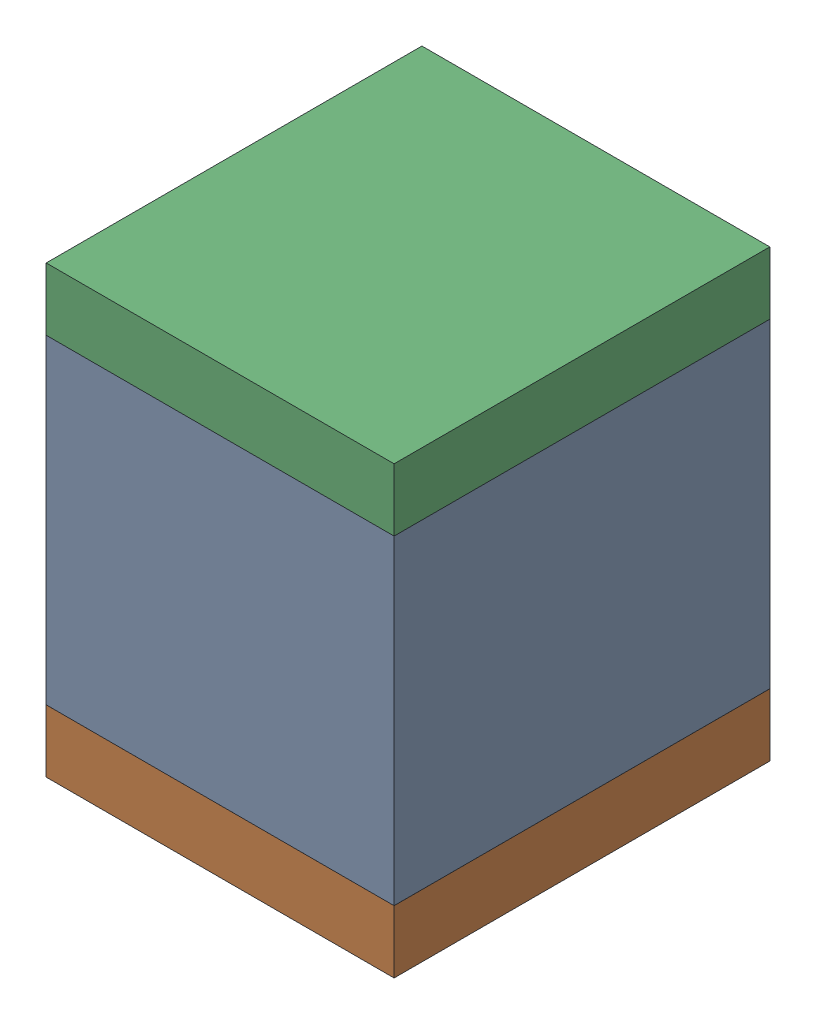
SolidWorks assembly C10, configuration ﾃﾞﾌｫﾙﾄ. Lengths in mm.
Overall size (2.5 3.2 2.7).
6 component instances, 2 part files, 0 mates.
Components (placement in the parent):
- 689260016-1: 689260016 [ﾃﾞﾌｫﾙﾄ] at (50.5 58.5 0) size (2.5 2.3 2.7)
  - Extruded_6-1: Extruded_6 [ﾃﾞﾌｫﾙﾄ] at origin size (2.5 2.3 2.7)
- 689260152-1: 689260152 [ﾃﾞﾌｫﾙﾄ] at (50.5001 57.125 0) size (2.5 0.45 2.7)
  - Extruded_7-1: Extruded_7 [ﾃﾞﾌｫﾙﾄ] at origin size (2.5 0.45 2.7)
- 689260152-2: 689260152 [ﾃﾞﾌｫﾙﾄ] at (50.5001 59.875 0) size (2.5 0.45 2.7)
  - Extruded_7-1: Extruded_7 [ﾃﾞﾌｫﾙﾄ] at origin size (2.5 0.45 2.7)
